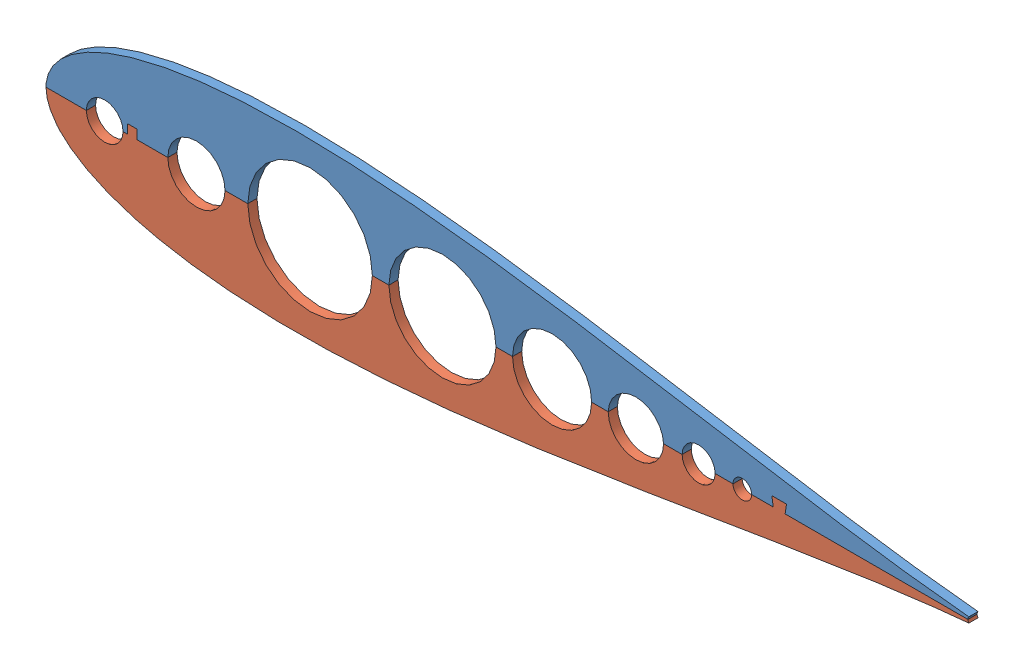
SolidWorks assembly Assembly Trimtab Airfoil, configuration Default. Lengths in mm.
Overall size (282.43 40.26 4.23).
2 component instances, 2 part files, 3 mates.
Components (placement in the parent):
- Trim Tab Airfoil Full Female-1: Trim Tab Airfoil Full Female [Default] at (-297.8956 -20.5316 28.5466) size (281.79 38.82 4.23)
- Trim Tab Airfoil Full Male-1: Trim Tab Airfoil Full Male [Default] at (-298.5353 16.6359 28.5476) size (282.43 38.64 4.23)
Mates (geometry in assembly coordinates):
- Coincident4: coincident: point of Trim Tab Airfoil Full Female-1; point of Trim Tab Airfoil Full Male-1
- Coincident5: coincident: point of Trim Tab Airfoil Full Female-1; point of Trim Tab Airfoil Full Male-1
- Coincident6: coincident aligned: plane of Trim Tab Airfoil Full Female-1 through (-130.1955 -1.8433 32.7805) normal (0 0 1); plane of Trim Tab Airfoil Full Male-1 through (-130.1955 -1.8433 32.7805) normal (0 0 1)
